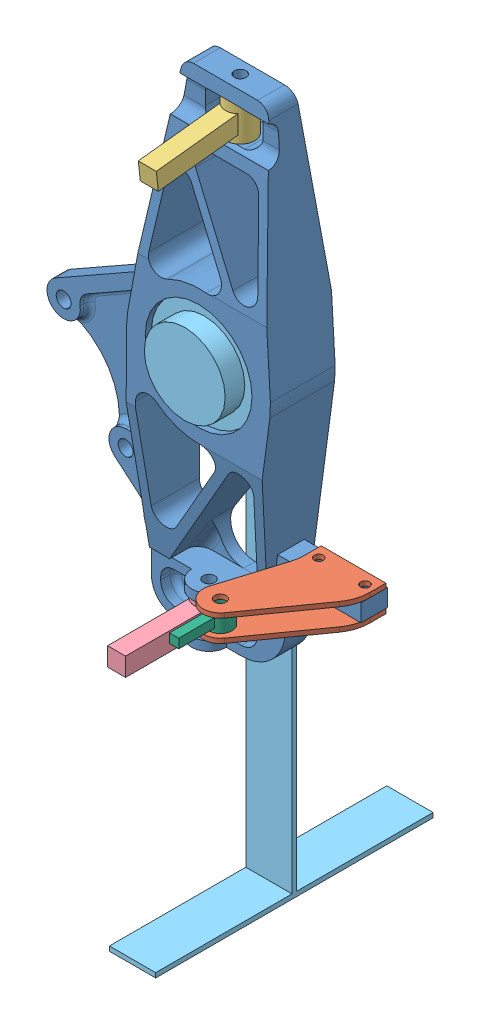
SolidWorks assembly Front Right Upright Simulation, configuration Default. Lengths in mm.
Overall size (170.64 402.39 166.16).
6 component instances, 6 part files, 14 mates.
Components (placement in the parent):
- Front Right Upright-1: Front Right Upright [Default] at (119.6265 153.8619 195.4936) size (170.64 276.57 35.56)
- Front Upright Steering Arm-1: Front Upright Steering Arm [Default] at (156.2372 66.4117 237.9199) x (0 0 -1) z (0 1 0) size (62.43 47.53 14.61)
- Front Upper A-Arm Spherical Joint-1: Front Upper A-Arm Spherical Joint [Default] at (127.8778 271.8619 198.6686) x (0 0 1) z (-1 0 0) size (58.99 20.73 15.88)
- Lower A-Arm Spherical Joint-2: Lower A-Arm Spherical Joint [Default] at (110.7458 26.8619 198.6686) x (0 0 -1) z (1 0 0) size (58.74 17.6 15.88)
- Front Hub and Tire-1: Front Hub and Tire [Default] at (119.6265 153.8619 195.4936) size (58.42 295.91 152.4)
- Steering Link Rod End-1: Steering Link Rod End [Default] at (156.2372 66.4117 237.9199) x (0 0 1) z (-1 0 0) size (31.75 9.53 12.7)
Mates (geometry in assembly coordinates):
- Coincident4: coincident anti-aligned: plane of Front Right Upright-1 through (112.0028 281.933 177.7136) normal (0 -1 0); plane of Front Upper A-Arm Spherical Joint-1 through (127.8778 281.933 198.6686) normal (0 1 0)
- Concentric5: concentric anti-aligned: circle of Front Right Upright-1; circle of Front Upper A-Arm Spherical Joint-1
- Parallel1: parallel anti-aligned: plane of Front Upper A-Arm Spherical Joint-1 through (122.9248 266.813 198.1076) normal (-1 0 0); plane of assembly through (0 0 0) normal (1 0 0)
- Coincident8: coincident anti-aligned: plane of Front Right Upright-1 through (119.6265 35.663 209.4636) normal (0 -1 0); plane of Lower A-Arm Spherical Joint-2 through (110.7458 35.663 198.6686) normal (0 1 0)
- Concentric7: concentric aligned: cylinder of Front Right Upright-1 through (110.7458 3.821 198.6686) axis (0 1 0) radius 3.2385; circle of Lower A-Arm Spherical Joint-2
- Parallel3: parallel aligned: plane of Lower A-Arm Spherical Joint-2 through (115.6988 31.9419 198.6686) normal (1 0 0); plane of assembly through (0 0 0) normal (1 0 0)
- Concentric9: concentric aligned: cylinder of Front Right Upright-1 through (119.6265 153.8619 177.7136) axis (0 0 1) radius 29.3434; circle of Front Hub and Tire-1
- Coincident12: coincident aligned: plane of Front Right Upright-1 through (119.6265 153.8619 195.4936) normal (0 0 1); plane of Front Hub and Tire-1 through (119.6265 153.8619 195.4936) normal (0 0 1)
- Parallel5: parallel aligned: plane of Front Hub and Tire-1 through (132.3265 135.6229 174.6336) normal (1 0 0); plane of assembly through (0 0 0) normal (1 0 0)
- Coincident13: coincident anti-aligned: plane of Front Upright Steering Arm-1 through (156.2372 71.1742 237.9199) normal (0 -1 0); plane of Steering Link Rod End-1 through (156.2372 71.1742 237.9199) normal (0 1 0)
- Parallel6: parallel anti-aligned: plane of Steering Link Rod End-1 through (153.6972 68.9517 263.3199) normal (-1 0 0); plane of assembly through (0 0 0) normal (1 0 0)
- Coincident14: coincident aligned: circle of Front Right Upright-1; circle of Front Upright Steering Arm-1
- Concentric10: concentric anti-aligned: cylinder of Front Right Upright-1 through (189.1617 12.9808 191.3661) axis (0 1 0) radius 2.4765; cylinder of Front Upright Steering Arm-1 through (189.1617 73.7142 191.3661) axis (0 -1 0) radius 2.4765
- Coincident15: coincident aligned: circle of Front Upright Steering Arm-1; circle of Steering Link Rod End-1
